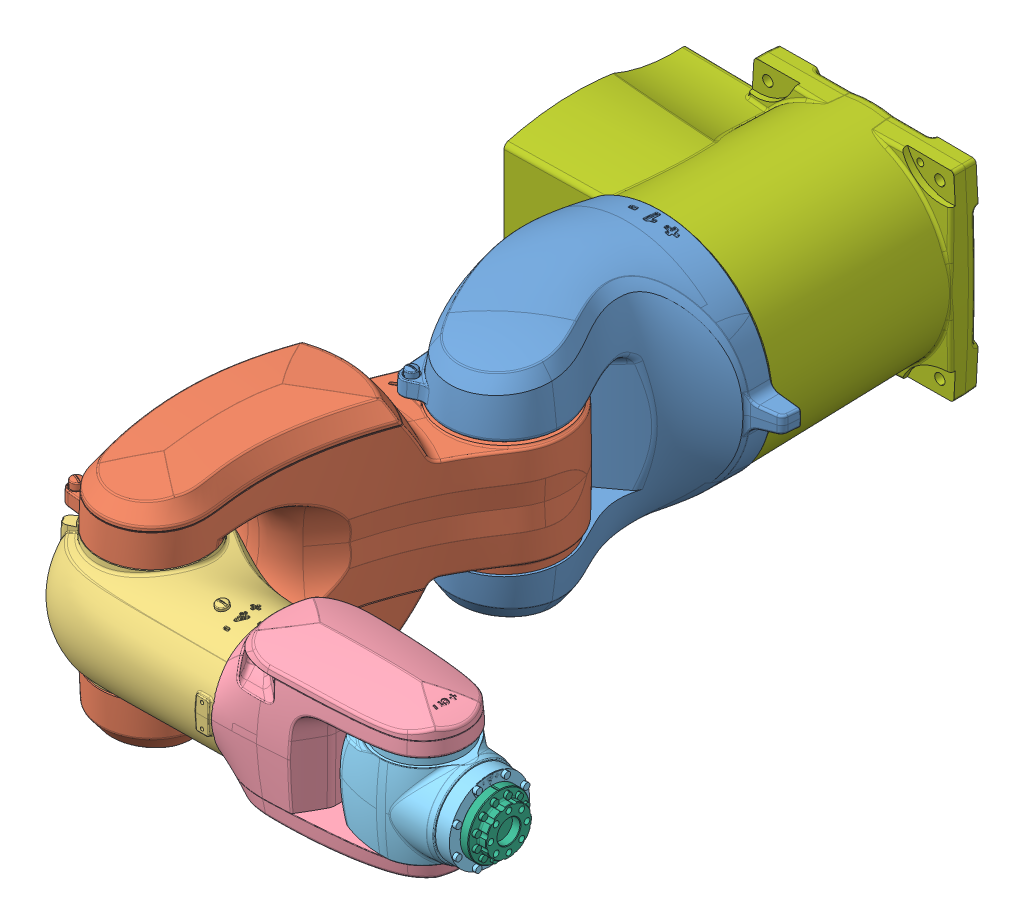
SolidWorks assembly Assem1, configuration Default. Lengths in mm.
Overall size (453.25 200.16 673.32).
7 component instances, 7 part files, 12 mates.
Components (placement in the parent):
- A1-1: A1 [Default] at (130.7022 342.8341 -95.9109) size (235.08 200.16 244.64)
- A2-1: A2 [Default] at (200.5358 342.8341 -92.8781) x (0.979544 0 0.20123) z (-0.20123 0 0.979544) size (158.35 196.41 361.26)
- A3-1: A3 [Default] at (78.3823 342.8341 -101.2295) size (188.7 119.2 134.23)
- A4-1: A4 [Default] at (74.6823 342.8341 -101.2295) size (190.81 135.68 101.83)
- A5-1: A5 [Default] at (74.6823 337.8341 -101.2295) size (116.5 90 90.55)
- A6-1: A6 [Default] at (74.6823 337.8341 -101.2295) size (16 53.99 54)
- Base-1: Base [Default] at (130.7022 342.8341 -95.9109) size (254.25 186.59 202.34)
Mates (geometry in assembly coordinates):
- Concentric2: concentric anti-aligned: cylinder of A1-1 through (130.7022 342.8341 89.0891) axis (0 0 -1) radius 50; cylinder of Base-1 through (130.7022 342.8341 -95.9109) axis (0 0 1) radius 50
- Coincident1: coincident anti-aligned: plane of A1-1 through (130.7022 342.8341 78.0891) normal (0 0 -1); plane of Base-1 through (166.9522 342.8341 78.0891) normal (0 0 1)
- Concentric4: concentric aligned: cylinder of A1-1 through (150.7022 388.2341 249.0891) axis (0 1 0) radius 37.5; cylinder of A2-1 through (150.7022 388.2341 249.0891) axis (0 1 0) radius 37.5
- Concentric5: concentric aligned: cylinder of A2-1 through (98.3823 381.0341 503.7705) axis (0 1 0) radius 40; cylinder of A3-1 through (98.3823 381.0341 503.7705) axis (0 1 0) radius 40
- Coincident4: coincident anti-aligned: plane of A2-1 through (98.3823 402.0341 503.7705) normal (0 -1 0); plane of A3-1 through (98.3823 402.0341 503.7705) normal (0 1 0)
- Coincident5: coincident anti-aligned: plane of A3-1 through (211.5823 383.3341 523.7705) normal (1 0 0); plane of A4-1 through (211.5823 342.8341 523.7705) normal (-1 0 0)
- Concentric7: concentric aligned: cylinder of A3-1 through (232.5823 342.8341 523.7705) axis (-1 0 0) radius 44; cylinder of A4-1 through (219.9823 342.8341 523.7705) axis (-1 0 0) radius 38
- Concentric8: concentric anti-aligned: circle of A4-1; circle of A5-1
- Coincident7: coincident anti-aligned: plane of A4-1 through (424.6823 381.8341 473.7705) normal (0 -1 0); plane of A5-1 through (354.6823 381.8341 523.7705) normal (0 1 0)
- Coincident9: coincident anti-aligned: plane of A1-1 through (150.7022 399.2341 249.0891) normal (0 -1 0); plane of A2-1 through (150.7022 399.2341 249.0891) normal (0 1 0)
- Coincident10: coincident anti-aligned: plane of A5-1 through (418.6823 337.8341 523.7705) normal (1 0 0); plane of A6-1 through (418.6823 362.8341 523.7705) normal (-1 0 0)
- Concentric10: concentric aligned: cylinder of A5-1 through (412.6823 337.8341 523.7705) axis (1 0 0) radius 25; cylinder of A6-1 through (442.1754 337.8341 523.7705) axis (1 0 0) radius 25
